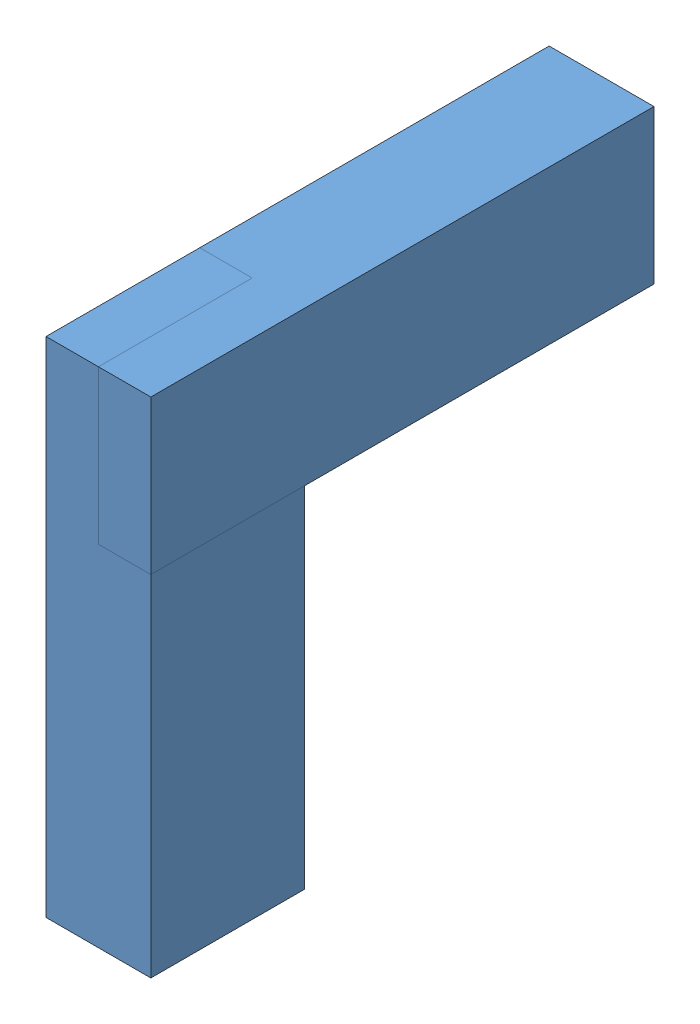
SolidWorks assembly CORNER LAP ASS, configuration Default. Lengths in mm.
Overall size (30 144 144).
2 component instances, 1 part files, 2 mates.
Components (placement in the parent):
- LAP JOINT-1: LAP JOINT [Default] at (-99.7424 -29.0894 22) size (30 144 44)
- LAP JOINT-2: LAP JOINT [Default] at (-69.7424 114.9106 -122) x (-1 0 0) z (0 1 0) size (30 144 44)
Mates (geometry in assembly coordinates):
- Coincident3: coincident anti-aligned: plane of LAP JOINT-1 through (-84.7424 70.9106 -22) normal (0 1 0); plane of LAP JOINT-2 through (-69.7424 70.9106 -122) normal (0 -1 0)
- Coincident5: coincident aligned: line of LAP JOINT-1 through (-84.7424 70.9106 22) axis (0 1 0); line of LAP JOINT-2 through (-84.7424 70.9106 22) axis (0 1 0)
